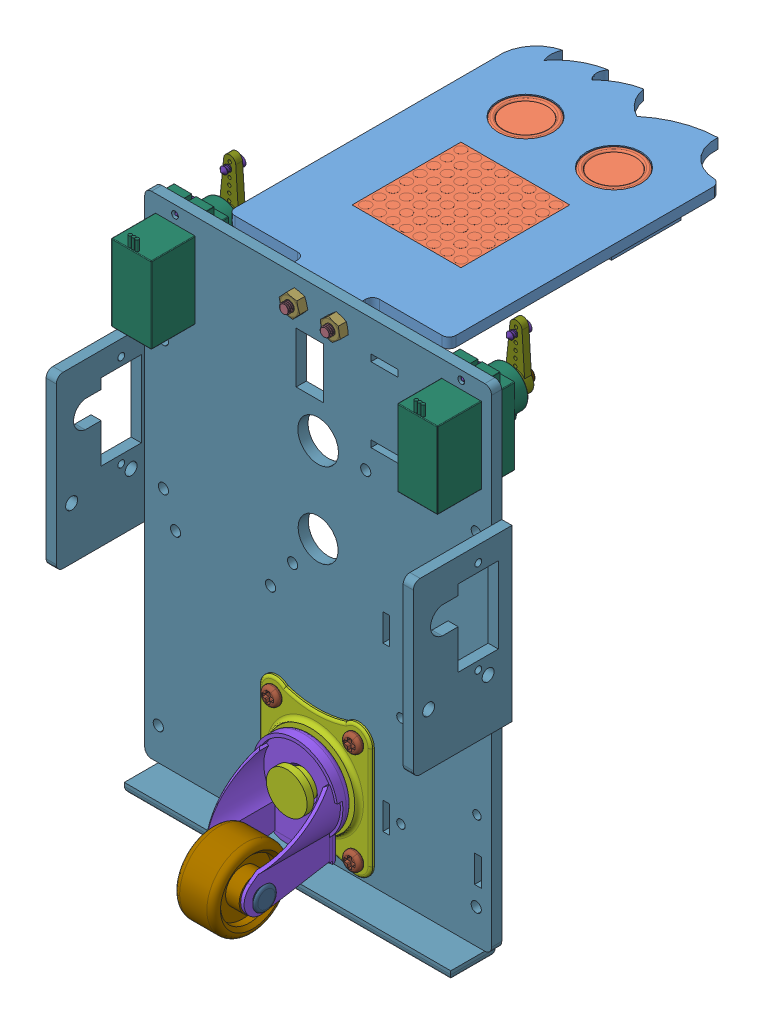
SolidWorks assembly DYOR_3D_LM_PU, configuration Predeterminado. Lengths in mm.
Overall size (108 155.56 135.99).
49 component instances, 20 part files, 15 mates.
Components (placement in the parent):
- HC-SR04 Ping Sensor-1: HC-SR04 Ping Sensor [Default] at (9.418 28.7888 -61.4611) x (0 0 -1) z (0 1 0) size (25.18 45 18.07)
  - PCB-1: PCB [Default] at origin size (20.5 45 1.75)
  - Transducer-1: Transducer [Default] at (0 -13 13.25) x (1 0 0) z (0 -1 0) size (15.88 12 15.88)
  - Transducer-2: Transducer [Default] at (0 13 13.25) x (1 0 0) z (0 -1 0) size (15.88 12 15.88)
  - 3 Pin Header 90 Degree-1: 3 Pin Header 90 Degree [Default] at (8.4275 0 -1.25) x (-1 0 0) z (0 -1 0) size (8 7.82 10)
  - 14 Pin SMT-1: 14 Pin SMT [Default] at (-0.35 -18.5 -0.85) x (0 -1 0) z (1 0 0) size (6 1.6 8.8)
  - 14 Pin SMT-2: 14 Pin SMT [Default] at (0 -0.3826 -0.85) x (1 0 0) z (0 1 0) size (6 1.6 8.8)
  - 14 Pin SMT-3: 14 Pin SMT [Default] at (0 17.5274 -0.85) x (1 0 0) z (0 1 0) size (6 1.6 8.8)
  - Cap1 SMT-1: Cap1 SMT [Default] at (-1.755 7.4774 -0.9689) x (0 1 0) z (-1 0 0) size (4.5 1.84 1.75)
  - Cap1 SMT-2: Cap1 SMT [Default] at (6.835 7.4774 -0.9689) x (0 1 0) z (-1 0 0) size (4.5 1.84 1.75)
  - Cap1 SMT-3: Cap1 SMT [Default] at (-6.835 7.4774 -0.9689) x (0 1 0) z (-1 0 0) size (4.5 1.84 1.75)
  - Cap1 SMT-4: Cap1 SMT [Default] at (4.295 7.4774 -0.9689) x (0 1 0) z (-1 0 0) size (4.5 1.84 1.75)
  - Cap1 SMT-5: Cap1 SMT [Default] at (1.755 7.4774 -0.9689) x (0 1 0) z (-1 0 0) size (4.5 1.84 1.75)
  - Cap1 SMT-6: Cap1 SMT [Default] at (-4.295 7.4774 -0.9689) x (0 1 0) z (-1 0 0) size (4.5 1.84 1.75)
  - HC-SR04 Crystal-1: HC-SR04 Crystal [Default] at (-8.3 0 1.75) x (0 -1 0) z (0 0 1) size (10 3.5 2.7)
- CA-1: CA [Predeterminado] at (-2.2402 -1.1323 0) x (1 0.000939 0) z (0 0 1) size (33 45.94 43.2)
  - Caster Wheel-1: Caster Wheel [Default] at (57.6387 -78.841 57.7572) x (0 1 0) z (-1 0 0) size (45.94 37.59 33)
    - caster holder-1: caster holder [Default] at (-24.0751 44.7184 29.5137) x (1 0 0) z (0 0 -1) size (39 9.27 33)
    - holder-1: holder [Default] at (-1.5751 42.9484 46.0137) x (0 0 1) z (1 0 0) size (25 28.07 31.31)
    - caster wheel-1: caster wheel [Default] at (-15.6961 19.9484 46.0137) x (0.997275 0.073773 0) z (0 0 1) size (23 23 14)
    - Part4-1: Part4 [Default] at (-15.6961 19.9484 55.0137) x (-0.978448 0.206495 0) z (0 0 -1) size (7 7 20)
  - M3x6 Philips Screw-1: M3x6 Philips Screw [Predeterminado] at (23.625 -65.4161 13.5389) size (5.3 5.3 7.81)
  - M3x6 Philips Screw-2: M3x6 Philips Screw [Predeterminado] at (-0.375 -65.4161 13.5389) size (5.3 5.3 7.81)
  - M3x6 Philips Screw-3: M3x6 Philips Screw [Predeterminado] at (-0.375 -95.4161 13.5389) size (5.3 5.3 7.81)
  - M3x6 Philips Screw-4: M3x6 Philips Screw [Predeterminado] at (23.625 -95.4161 13.5389) size (5.3 5.3 7.81)
  - M3 Nut-1: M3 Nut [Predeterminado] at (23.625 -65.4161 11.0389) size (6.27 6.27 2.71)
  - M3 Nut-2: M3 Nut [Predeterminado] at (-0.375 -65.4161 11.0389) size (6.27 6.27 2.71)
  - M3 Nut-3: M3 Nut [Predeterminado] at (-0.375 -95.4161 11.0389) size (6.27 6.27 2.71)
  - M3 Nut-4: M3 Nut [Predeterminado] at (23.625 -95.4161 11.0389) size (6.27 6.27 2.71)
- M3x10 Philips Screw-2: M3x10 Philips Screw [Predeterminado] at (3.418 36.0388 6.5389) x (0.88719 -0.461404 0) z (0 0 -1) size (5.3 5.3 11.8)
- M3x10 Philips Screw-3: M3x10 Philips Screw [Predeterminado] at (15.418 36.0388 6.5389) x (0.471193 -0.88203 0) z (0 0 -1) size (5.3 5.3 11.8)
- M3 Nut-1: M3 Nut [Predeterminado] at (3.418 36.0388 16.5389) x (0.222076 0.975029 0) z (0 0 1) size (6.27 6.27 2.71)
- M3 Nut-2: M3 Nut [Predeterminado] at (15.418 36.0388 11.0389) x (-0.334718 -0.942319 0) z (0 0 -1) size (6.27 6.27 2.71)
- BasePU-1: BasePU [Predeterminado] at (-51.2528 96.5598 9.5389) size (108 147.56 29)
- PU-1: PU [Predeterminado] at (-155.9776 204.2742 -130.283) size (95.94 37.23 33.31)
  - sg90-1: sg90 [Default] at (201.5956 -166.7354 155.7219) x (0 -1 0) z (1 0 0) size (31.9 29.9 11.8)
  - sg90-2: sg90 [Default] at (117.452 -166.7354 155.7219) x (0 -1 0) z (1 0 0) size (31.9 29.9 11.8)
  - SG90 plastic Horn-1: SG90 plastic Horn [Default] at (123.352 -172.6354 127.0219) x (0.017141 0.999853 0) z (-0.999853 0.017141 0) size (19.4 4 7.07)
  - SG90 plastic Horn-2: SG90 plastic Horn [Default] at (207.4956 -172.6354 127.0219) x (0.020276 0.999794 0) z (-0.999794 0.020276 0) size (19.4 4 7.07)
  - M2x6 SelfTap Screw-1: M2x6 SelfTap Screw [Predeterminado] at (207.4956 -164.3354 136.8219) x (-0.923728 -0.383049 0) z (0 0 -1) size (3.4 3.28 6)
  - M2x6 SelfTap Screw-2: M2x6 SelfTap Screw [Predeterminado] at (207.4956 -191.6354 136.3219) x (-0.923728 -0.383049 0) z (0 0 -1) size (3.4 3.28 6)
  - M2x6 SelfTap Screw-3: M2x6 SelfTap Screw [Predeterminado] at (123.352 -164.3354 136.8219) x (-0.993348 0.115149 0) z (0 0 -1) size (3.4 3.28 6)
  - M2x6 SelfTap Screw-4: M2x6 SelfTap Screw [Predeterminado] at (123.352 -191.6354 136.8219) x (-0.923728 -0.383049 0) z (0 0 -1) size (3.4 3.28 6)
  - (M2_3_mm)_90116A007_METRIC 316 SS PAN HEAD PHILLIPS MACHINE SCREW-1: (M2_3_mm)_90116A007_METRIC 316 SS PAN HEAD PHILLIPS MACHINE SCREW [90116A007] at (123.352 -172.6354 127.0219) x (-0.923728 -0.383049 0) z (0 0 -1) size (4 4 4.68)
  - (M2_3_mm)_90116A007_METRIC 316 SS PAN HEAD PHILLIPS MACHINE SCREW-2: (M2_3_mm)_90116A007_METRIC 316 SS PAN HEAD PHILLIPS MACHINE SCREW [90116A007] at (207.4956 -172.6354 127.0219) x (-0.923728 -0.383049 0) z (0 0 -1) size (4 4 4.68)
  - M2x6 SelfTap Screw-5: M2x6 SelfTap Screw [Predeterminado] at (123.352 -160.1354 123.5219) x (-0.923728 -0.383049 0) z (0 0 -1) size (3.4 3.28 6)
  - M2x6 SelfTap Screw-6: M2x6 SelfTap Screw [Predeterminado] at (207.4956 -160.1354 123.5219) x (-0.923728 -0.383049 0) z (0 0 -1) size (3.4 3.28 6)
- Front_LM-1: Front_LM [Predeterminado] at (-49.2809 42.5388 -46.4821) x (1 0 0) z (0 1 0) size (65 95.41 11)
- max7219_compact_board-1: max7219_compact_board [Predeterminado] at (15.918 28.3388 -29.4611) x (1 0 0) z (0 1 0) size (34 32 21.83)
Mates (geometry in assembly coordinates):
- Concéntrica15: concentric: circle of M3 Nut-2; circle of BasePU-1
- Coincidente15: coincident: plane of M3 Nut-1 through (3.418 36.0388 12.5389) normal (0 0 -1); plane of BasePU-1 through (58.418 40.5388 12.5389) normal (0 0 1)
- Coincidente16: coincident: plane of M3 Nut-2 through (15.418 36.0388 12.5389) normal (0 0 -1); plane of BasePU-1 through (58.418 40.5388 12.5389) normal (0 0 1)
- Coincidente17: coincident: plane of BasePU-1 through (57.418 37.5388 12.5389) normal (0 -1 0); plane of PU-1/sg90-1 through (57.418 37.5388 25.4389) normal (0 1 0)
- Coincidente18: coincident: plane of BasePU-1 through (58.418 40.5388 9.5389) normal (0 0 -1); plane of PU-1/sg90-1 through (57.418 10.3388 9.5389) normal (0 0 1)
- Concéntrica16: concentric: circle of BasePU-1; circle of PU-1/M2x6 SelfTap Screw-2
- Coincidente19: coincident: plane of BasePU-1 through (58.418 40.5388 9.5389) normal (0 0 -1); plane of Front_LM-1 through (-0.582 39.5388 9.5389) normal (0 0 1)
- Concéntrica17: concentric: circle of BasePU-1; circle of Front_LM-1
- Paralelo1: parallel: plane of BasePU-1 through (-7.6975 42.5388 12.5389) normal (0 1 0); plane of Front_LM-1 through (-2.582 42.5388 8.5389) normal (0 1 0)
- Concéntrica18: concentric: circle of HC-SR04 Ping Sensor-1/Transducer-1; circle of Front_LM-1
- Concéntrica19: concentric: circle of HC-SR04 Ping Sensor-1/Transducer-2; circle of Front_LM-1
- Coincidente21: coincident: plane of HC-SR04 Ping Sensor-1/Transducer-2 through (-3.582 42.5388 -69.4011) normal (0 1 0); plane of Front_LM-1 through (-2.582 42.5388 8.5389) normal (0 1 0)
- Coincidente22: coincident: plane of Front_LM-1 through (25.418 39.5388 -45.4611) normal (0 0 1); plane of max7219_compact_board-1 through (-6.582 42.5388 -45.4611) normal (0 0 -1)
- Coincidente23: coincident: plane of Front_LM-1 through (25.418 39.5388 -13.4611) normal (-1 0 0); plane of max7219_compact_board-1 through (25.418 42.5388 -45.4611) normal (1 0 0)
- Coincidente24: coincident: plane of Front_LM-1 through (-2.582 42.5388 8.5389) normal (0 1 0); plane of max7219_compact_board-1 through (15.918 42.5388 -29.4611) normal (0 1 0)
